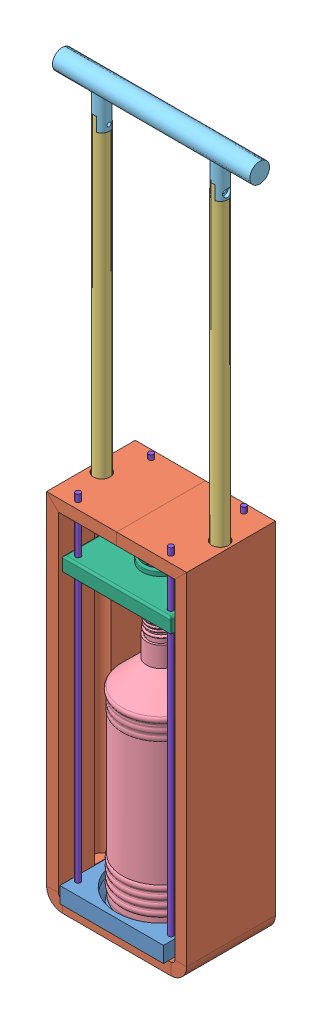
SolidWorks assembly The shrinker, configuration Default. Lengths in mm.
Overall size (200 714.8 100).
12 component instances, 8 part files, 22 mates.
Components (placement in the parent):
- bottle load-1: bottle load [Default] at (69.4638 76.8825 55.0523) x (1 0 0) z (0 0 -1) size (105 16 100)
- support mat-1: support mat [Default] at (69.4638 54.8825 55.0523) size (142 362 90)
- pressing point-1: pressing point [Default] at (69.4638 377.6793 55.0523) x (-1 0 0) z (0 0 -1) size (135 357.5 15)
- Battery Water Bottle HDPE-1: Battery Water Bottle HDPE [Default] at (69.4638 66.0825 55.0523) size (81.4 253.7 81.4)
- hand-1: hand [Default] at (69.4638 753.6793 55.0523) x (0 0 1) z (1 0 0) size (20 50 200)
- top_shrinker-2: top_shrinker [Default] at (69.4638 368.6793 55.0523) x (-1 0 0) z (0 -1 0) size (110 90 29)
- holder-1: holder [Default] at (107.0415 392.6793 55.0523) x (0 0 1) z (0 -1 0) size (30 15 9)
- holder-2: holder [Default] at (31.8862 392.6793 55.0523) x (0 0 -1) z (0 -1 0) size (30 15 9)
- guidage-1: guidage [Default] at (116.4638 58.2714 92.0523) x (0.67309 0 -0.73956) z (0.73956 0 0.67309) size (5 360 5)
- guidage-2: guidage [Default] at (22.4638 58.2301 92.0523) x (0.059609 0 0.998222) z (-0.998222 0 0.059609) size (5 360 5)
- guidage-3: guidage [Default] at (116.4638 56.8278 18.0523) x (0.363061 0 -0.931765) z (0.931765 0 0.363061) size (5 360 5)
- guidage-4: guidage [Default] at (22.4638 55.7969 18.0523) x (0.648295 0 -0.761389) z (0.761389 0 0.648295) size (5 360 5)
Mates (geometry in assembly coordinates):
- Coincident6: coincident anti-aligned: plane of bottle load-1 through (69.4638 60.8825 55.0523) normal (0 -1 0); plane of support mat-1 through (124.4638 60.8825 10.0523) normal (0 1 0)
- Concentric2: concentric anti-aligned: circle of bottle load-1; circle of support mat-1
- Concentric4: concentric anti-aligned: circle of support mat-1; circle of pressing point-1
- Concentric5: concentric anti-aligned: circle of support mat-1; circle of pressing point-1
- Concentric6: concentric anti-aligned: circle of bottle load-1; circle of support mat-1
- Tangent1: tangent anti-aligned: plane of bottle load-1 through (69.4638 64.8825 55.0523) normal (0 1 0); torus of Battery Water Bottle HDPE-1
- Concentric7: concentric anti-aligned: circle of bottle load-1; circle of Battery Water Bottle HDPE-1
- Coincident7: coincident anti-aligned: plane of pressing point-1 through (131.4638 713.6793 62.5523) normal (1 0 0); plane of hand-1 through (131.4638 727.6793 47.5523) normal (-1 0 0)
- Concentric8: concentric anti-aligned: circle of pressing point-1; circle of hand-1
- Coincident8: coincident anti-aligned: plane of pressing point-1 through (9.4638 727.6793 55.0523) normal (0 1 0); plane of hand-1 through (69.4638 727.6793 55.0523) normal (0 -1 0)
- Concentric10: concentric anti-aligned: cylinder of pressing point-1 through (119.4638 377.6793 55.0523) axis (-1 0 0) radius 7.5; cylinder of top_shrinker-2 through (14.4638 377.6793 55.0523) axis (1 0 0) radius 7.5
- Concentric11: concentric anti-aligned: circle of Battery Water Bottle HDPE-1; circle of top_shrinker-2
- Coincident12: coincident aligned: circle of top_shrinker-2; circle of holder-1
- Concentric12: concentric aligned: circle of top_shrinker-2; circle of holder-1
- Concentric13: concentric aligned: circle of top_shrinker-2; circle of holder-2
- Concentric14: concentric aligned: circle of top_shrinker-2; circle of holder-2
- Coincident16: coincident anti-aligned: line of top_shrinker-2 through (39.3862 377.6793 40.0523) axis (-1 0 0); line of holder-2 through (24.3862 377.6793 40.0523) axis (1 0 0)
- LimitDistance1: limit distance = 12.2032 mm: cylinder of holder-1 through (99.5415 377.6793 55.0523) axis (1 0 0) radius 9; plane of support mat-1 through (69.4638 398.8825 10.0523) normal (0 -1 0)
- Concentric15: concentric aligned: circle of bottle load-1; circle of guidage-1
- Concentric17: concentric anti-aligned: circle of bottle load-1; circle of guidage-2
- Concentric18: concentric anti-aligned: circle of bottle load-1; circle of guidage-3
- Concentric19: concentric aligned: circle of bottle load-1; circle of guidage-4
